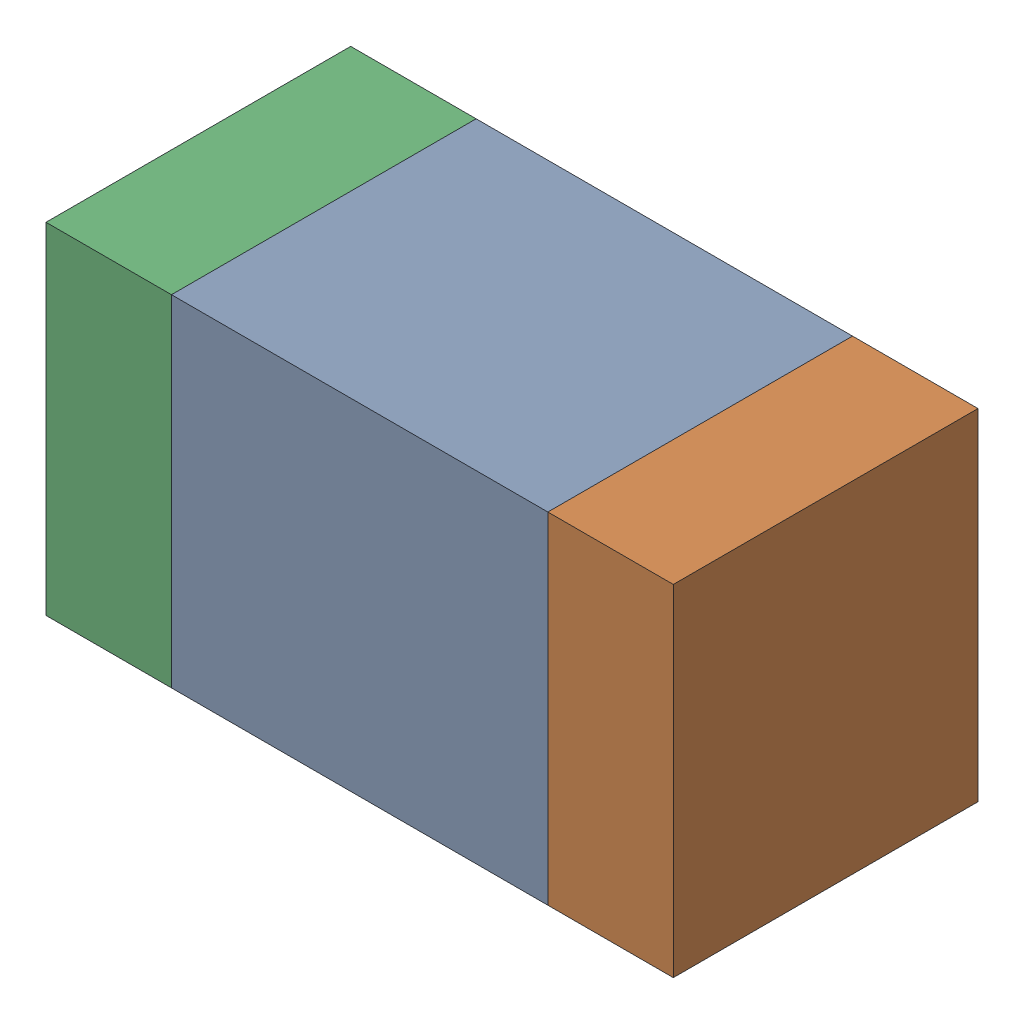
SolidWorks assembly C9, configuration 默认. Lengths in mm.
Overall size (1.75 0.95 0.85).
6 component instances, 2 part files, 0 mates.
Components (placement in the parent):
- 6241789056-1: 6241789056 [默认] at (8.509 5.715 0) size (1.05 0.95 0.85)
  - Extruded-4-1: Extruded-4 [默认] at origin size (1.05 0.95 0.85)
- 6241789456-1: 6241789456 [默认] at (9.209 5.715 0) size (0.35 0.95 0.85)
  - Extruded-5-1: Extruded-5 [默认] at origin size (0.35 0.95 0.85)
- 6241789456-2: 6241789456 [默认] at (7.809 5.715 0) size (0.35 0.95 0.85)
  - Extruded-5-1: Extruded-5 [默认] at origin size (0.35 0.95 0.85)
